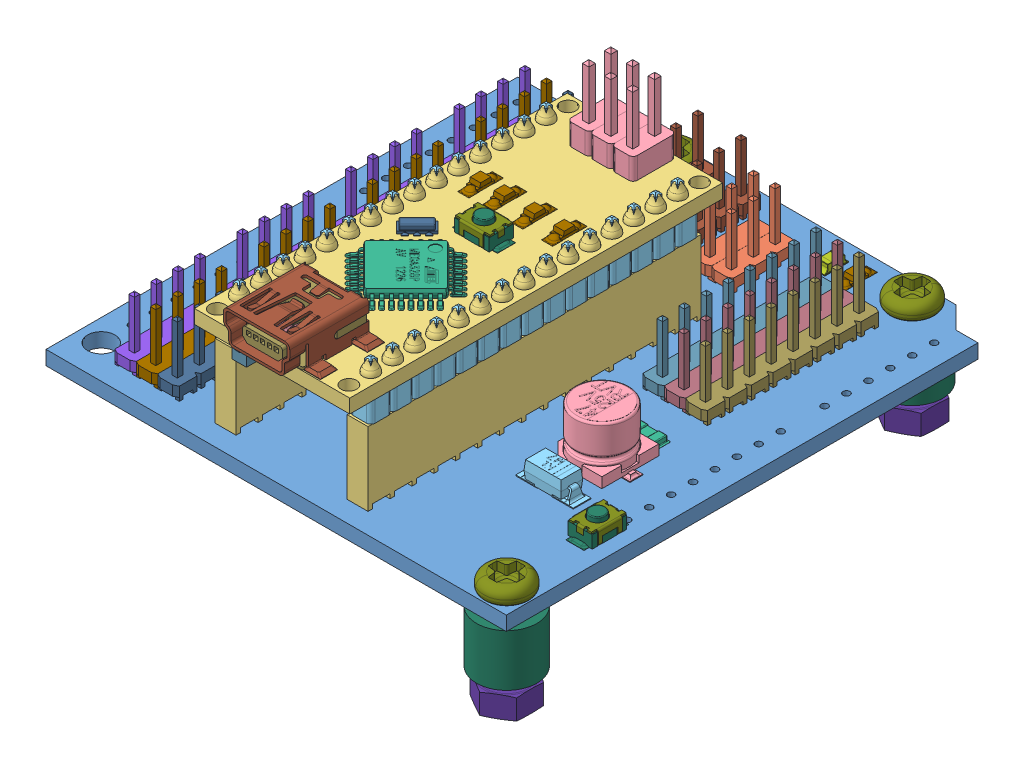
SolidWorks assembly Ensamblaje_Shield_NANO_spacer_screw_M3, configuration Predeterminado. Lengths in mm.
Overall size (54.3 32.38 59.87).
81 component instances, 35 part files, 24 mates.
Components (placement in the parent):
- Ensamblaje_Shield_NANO-2: Ensamblaje_Shield_NANO [Predeterminado] at (30.2087 16.5393 22.618) size (53.34 23.75 58.91)
  - Shield_Arduino NANO-1: Shield_Arduino NANO [Default] at (28.1337 3.1376 57.2) size (53.34 1.65 57.2)
  - Samtec-TLW-103-01-F-S-1: Samtec-TLW-103-01-F-S [Default] at (7.7639 4.0901 -3.1706) x (0 0 1) z (-1 0 0) size (7.62 10 2.49)
  - Samtec-TLW-103-01-F-S-2: Samtec-TLW-103-01-F-S [Default] at (5.2639 4.0901 -3.1706) x (0 0 1) z (-1 0 0) size (7.62 10 2.49)
  - arduino nano-1: arduino nano [Predeterminado] at (-6.7272 14.1466 6.3422) x (0 0 1) z (-1 0 0) size (45 18.6 18)
    - nano-board-1: nano-board [Predeterminado] at origin size (43.2 4.61 18)
    - 2pin_header__02-1: 2pin_header__02 [Predeterminado] at (-1.143 1.6 -7.62) size (5 11.75 2.54)
    - 2pin_header__02-2: 2pin_header__02 [Predeterminado] at (-1.143 1.6 -5.08) size (5 11.75 2.54)
    - 2pin_header__02-3: 2pin_header__02 [Predeterminado] at (-1.143 1.6 -10.16) size (5 11.75 2.54)
    - 15pin_header__-1: 15pin_header__ [Predeterminado] x (0 0 1) z (1 0 0) size (2.54 11.75 38.1)
    - 15pin_header__-2: 15pin_header__ [Predeterminado] at (0 0 -15.24) x (0 0 1) z (1 0 0) size (2.54 11.75 38.1)
    - atmega328-1: atmega328 [Predeterminado] at (23.85 1.75 -7.62) x (-0.707107 0 0.707107) z (-0.707107 0 -0.707107) size (10 1.1 10)
    - ftdi FT232rl-1: ftdi FT232rl [Predeterminado] at (29.05 0 -7.67) x (0 0 -1) z (-1 0 0) size (9.25 1.9 10.2)
    - smt_resistor222-1: smt_resistor222 [Predeterminado] at (21.86 0 -5.8) x (0 0 -1) z (-1 0 0) size (1.7 0.6 3.8)
    - smt_resistor222-2: smt_resistor222 [Predeterminado] at (21.86 0 -9) x (0 0 -1) z (-1 0 0) size (1.7 0.6 3.8)
    - smt_resistor222-3: smt_resistor222 [Predeterminado] at (36.75 0 -7.6) x (0 0 -1) z (-1 0 0) size (1.7 0.6 3.8)
    - smt_resistor222-4: smt_resistor222 [Predeterminado] at (36.75 0 -12) x (0 0 -1) z (-1 0 0) size (1.7 0.6 3.8)
    - smt_resistor222-5: smt_resistor222 [Predeterminado] at (8.2 0 -2.6) x (0 0 -1) z (-1 0 0) size (1.7 0.6 3.8)
    - led-1: led [Predeterminado] at (10.4 1.6 -2.8) size (4 0.9 1.55)
    - led-2: led [Predeterminado] at (10.4 1.6 -5.55) size (4 0.9 1.55)
    - led-3: led [Predeterminado] at (10.4 1.6 -12.5) size (4 0.9 1.55)
    - led-4: led [Predeterminado] at (10.4 1.6 -9.05) size (4 0.9 1.55)
    - 16mhz crystal - measured-1: 16mhz crystal - measured [Predeterminado] at (18.5113 1.6 -3.5541) x (0.707107 0 0.707107) z (-0.707107 0 0.707107) size (3.4 0.8 2.01)
    - MINIUSB - MEASURED-1: MINIUSB - MEASURED [Predeterminado] at (38.98 1.65 -7.62) x (0 0 1) z (-1 0 0) size (11.03 4.95 10.42)
      - MINIUSBSHELL-1: MINIUSBSHELL [Predeterminado] at origin size (11.03 3.97 9.48)
      - MINIUSBCORE-1: MINIUSBCORE [Predeterminado] at (0 0 6.7) x (-1 0 0) z (0 0 -1) size (7.7 4.5 8.2)
      - MINI USB CONTACT-1: MINI USB CONTACT [Predeterminado] at (-1.6 0 5.7) x (-1 0 0) z (0 0 -1) size (0.53 2.55 9.41)
      - MINI USB CONTACT-2: MINI USB CONTACT [Predeterminado] at (-0.8 0 5.7) x (-1 0 0) z (0 0 -1) size (0.53 2.55 9.41)
      - MINI USB CONTACT-3: MINI USB CONTACT [Predeterminado] at (0 0 5.7) x (-1 0 0) z (0 0 -1) size (0.53 2.55 9.41)
      - MINI USB CONTACT-4: MINI USB CONTACT [Predeterminado] at (0.8 0 5.7) x (-1 0 0) z (0 0 -1) size (0.53 2.55 9.41)
      - MINI USB CONTACT-5: MINI USB CONTACT [Predeterminado] at (1.6 0 5.7) x (-1 0 0) z (0 0 -1) size (0.53 2.55 9.41)
    - cap106C-1: cap106C [Predeterminado] at (37.2 0 -3.3) x (0 0 1) z (1 0 0) size (1.7 1.81 4)
    - cap106C-2: cap106C [Predeterminado] at (7.9 0 -5.6) x (0 0 -1) z (-1 0 0) size (1.7 1.81 4)
    - reset button-1: reset button [Predeterminado] at (15.25 1.6 -8.05) x (0 0 -1) z (1 0 0) size (5.21 2.15 3)
      - reset core-1: reset core [Predeterminado] at origin size (5.21 2.15 2.8)
      - reset shell-1: reset shell [Predeterminado] at (0 1.65 0) x (0 0 1) z (-1 0 0) size (3 1.65 4)
    - nano - reg-1: nano - reg [Predeterminado] at (6.1 0 -10.16) x (0 0 -1) z (-1 0 0) size (6.5 1.69 8.3)
    - NANO DIODE-1: NANO DIODE [Predeterminado] at (11.43 0 -4.2) x (0 0 1) z (1 0 0) size (4.92 1.38 1.7)
    - 189 RESISTOR PACK-1: 189 RESISTOR PACK [Predeterminado] at (15.75 0 -10.85) x (0 0 1) z (1 0 0) size (3.2 0.51 3)
    - 102 RESISTOR PACK-1: 102 RESISTOR PACK [Predeterminado] at (15.75 0 -5.2) x (0 0 1) z (1 0 0) size (3.2 0.51 3)
  - Samtec-SSW-115-01-F-S-3: Samtec-SSW-115-01-F-S [Default] at (8.5128 3.1376 24.1222) size (2.41 11.15 38.61)
  - Samtec-SSW-115-01-F-S-4: Samtec-SSW-115-01-F-S [Default] at (-6.7872 3.1376 24.1222) size (2.41 11.15 38.61)
  - 47uf CAP Dcase-1: 47uf CAP Dcase [Default] at (17.9906 3.1376 24.6048) x (0 0 -1) z (1 0 0) size (6.6 5.81 8)
  - m7 diode-1: m7 diode [Default] at (18.0456 3.1376 30.2824) size (6.66 2.35 2.5)
  - smt_resistor222_a-1: smt_resistor222_a [Default] at (18.3832 3.1376 19.7626) x (0 0 -1) z (1 0 0) size (1.7 0.6 3.8)
  - nano - reg-1: nano - reg [Predeterminado] at (1.246 3.1376 24.0398) x (0 0 1) z (-1 0 0) size (6.5 1.69 8.3)
  - cap106C-1: cap106C [Predeterminado] at (1.2297 3.1376 32.7528) x (0 0 1) z (-1 0 0) size (1.7 1.81 4)
  - smt_resistor222_a-2: smt_resistor222_a [Default] at (1.378 3.1376 29.6673) x (0 0 -1) z (1 0 0) size (1.7 0.6 3.8)
  - smt_resistor222_a-3: smt_resistor222_a [Default] at (1.364 3.1376 18.2634) x (0 0 -1) z (1 0 0) size (1.7 0.6 3.8)
  - cap106C-2: cap106C [Predeterminado] at (1.6627 3.1376 15.2796) x (0 0 1) z (-1 0 0) size (1.7 1.81 4)
  - led-1: led [Predeterminado] at (14.5957 3.1376 -8.0824) x (0 0 -1) z (1 0 0) size (4 0.9 1.55)
  - reset button-1: reset button [Predeterminado] at (25.102 3.1376 32.2333) x (0 0 -1) z (1 0 0) size (5.21 2.15 3)
    - reset core-1: reset core [Predeterminado] at origin size (5.21 2.15 2.8)
    - reset shell-1: reset shell [Predeterminado] at (0 1.65 0) x (0 0 1) z (-1 0 0) size (3 1.65 4)
  - blm21-1: blm21 [Default] at (11.9193 3.1376 -8.0299) x (0 0 -1) z (1 0 0) size (2.76 0.95 1.32)
  - Samtec-TLW-104-01-F-S_N-1: Samtec-TLW-104-01-F-S_N [Default] at (-18.4832 4.0901 38.492) x (0 0 -1) z (1 0 0) size (10.16 10 2.49)
  - Samtec-TLW-104-01-F-S_N-2: Samtec-TLW-104-01-F-S_N [Default] at (-18.4832 4.0901 25.942) x (0 0 -1) z (1 0 0) size (10.16 10 2.49)
  - Samtec-TLW-104-01-F-S_N-3: Samtec-TLW-104-01-F-S_N [Default] at (-18.4832 4.0901 13.392) x (0 0 -1) z (1 0 0) size (10.16 10 2.49)
  - Samtec-TLW-104-01-F-S_N-4: Samtec-TLW-104-01-F-S_N [Default] at (-18.4832 4.0901 0.842) x (0 0 -1) z (1 0 0) size (10.16 10 2.49)
  - Samtec-TLW-104-01-F-S_R-1: Samtec-TLW-104-01-F-S_R [Default] at (-15.994 4.0901 38.492) x (0 0 1) z (-1 0 0) size (10.16 10 2.49)
  - Samtec-TLW-104-01-F-S_R-2: Samtec-TLW-104-01-F-S_R [Default] at (-15.994 4.0901 25.942) x (0 0 1) z (-1 0 0) size (10.16 10 2.49)
  - Samtec-TLW-104-01-F-S_R-3: Samtec-TLW-104-01-F-S_R [Default] at (-15.994 4.0901 13.392) x (0 0 1) z (-1 0 0) size (10.16 10 2.49)
  - Samtec-TLW-104-01-F-S_R-4: Samtec-TLW-104-01-F-S_R [Default] at (-15.994 4.0901 0.842) x (0 0 1) z (-1 0 0) size (10.16 10 2.49)
  - Samtec-TLW-104-01-F-S_B-1: Samtec-TLW-104-01-F-S_B [Default] at (-13.5048 4.0901 38.492) x (0 0 -1) z (1 0 0) size (10.16 10 2.49)
  - Samtec-TLW-104-01-F-S_B-2: Samtec-TLW-104-01-F-S_B [Default] at (-13.5048 4.0901 25.942) x (0 0 -1) z (1 0 0) size (10.16 10 2.49)
  - Samtec-TLW-104-01-F-S_B-3: Samtec-TLW-104-01-F-S_B [Default] at (-13.5048 4.0901 13.392) x (0 0 -1) z (1 0 0) size (10.16 10 2.49)
  - Samtec-TLW-104-01-F-S_B-4: Samtec-TLW-104-01-F-S_B [Default] at (-13.5048 4.0901 0.842) x (0 0 -1) z (1 0 0) size (10.16 10 2.49)
  - Samtec-TLW-104-01-F-S_W-1: Samtec-TLW-104-01-F-S_W [Default] at (-4.0059 4.0901 -4.7024) x (0 0 -1) z (1 0 0) size (10.16 10 2.49)
  - Samtec-TLW-104-01-F-S_W-2: Samtec-TLW-104-01-F-S_W [Default] at (0.9469 4.0901 -4.7452) x (0 0 -1) z (1 0 0) size (10.16 10 2.49)
  - Samtec-TLW-108-01-F-S_B-1: Samtec-TLW-108-01-F-S_B [Default] at (19.5362 4.0901 5.2512) x (0 0 -1) z (1 0 0) size (20.32 10 2.49)
  - Samtec-TLW-108-01-F-S_R-1: Samtec-TLW-108-01-F-S_R [Default] at (17.047 4.0901 5.2512) x (0 0 1) z (-1 0 0) size (20.32 10 2.49)
  - Samtec-TLW-108-01-F-S_N-1: Samtec-TLW-108-01-F-S_N [Default] at (14.5578 4.0901 5.2512) x (0 0 1) z (-1 0 0) size (20.32 10 2.49)
- separador-1: separador [Predeterminado] at (55.8024 18.0269 65.848) x (1 0 0) z (0 -1 0) size (7 7 6)
- M3x10 Philips Screw-1: M3x10 Philips Screw [Predeterminado] at (55.8024 19.6769 65.848) x (1 0 0) z (0 1 0) size (5.3 5.3 11.8)
- M3 Nut-1: M3 Nut [Predeterminado] at (55.8024 12.5269 65.848) x (1 0 0) z (0 1 0) size (6.27 6.27 2.71)
- M3 Nut-2: M3 Nut [Predeterminado] at (50.7224 7.0269 13.778) x (0.999652 0 0.026398) z (0 -1 0) size (6.27 6.27 2.71)
- separador-2: separador [Predeterminado] at (50.7224 18.0269 13.778) x (1 0 0) z (0 -1 0) size (7 7 6)
- M3x10 Philips Screw-2: M3x10 Philips Screw [Predeterminado] at (50.7224 19.6769 13.778) x (1 0 0) z (0 1 0) size (5.3 5.3 11.8)
- M3x10 Philips Screw-3: M3x10 Philips Screw [Predeterminado] at (22.7824 19.6769 13.778) x (1 0 0) z (0 1 0) size (5.3 5.3 11.8)
- separador-3: separador [Predeterminado] at (22.7824 18.0269 13.778) x (1 0 0) z (0 -1 0) size (7 7 6)
- M3 Nut-3: M3 Nut [Predeterminado] at (22.7824 7.0269 13.778) x (1 0 0) z (0 -1 0) size (6.27 6.27 2.71)
Mates (geometry in assembly coordinates):
- Coincidente2: coincident: plane of Ensamblaje_Shield_NANO-2/Shield_Arduino NANO-1 through (58.3424 18.0269 79.818) normal (0 -1 0); plane of ? through (22.7824 18.0269 13.778) normal (0 1 0)
- Coincidente3: coincident: plane of Ensamblaje_Shield_NANO-2/Shield_Arduino NANO-1 through (58.3424 18.0269 79.818) normal (0 -1 0); plane of ? through (55.8024 18.0269 65.848) normal (0 1 0)
- Coincidente4: coincident: plane of Ensamblaje_Shield_NANO-2/Shield_Arduino NANO-1 through (58.3424 18.0269 79.818) normal (0 -1 0); plane of ? through (50.7224 18.0269 13.778) normal (0 1 0)
- Concéntrica2: concentric: circle of Ensamblaje_Shield_NANO-2/Shield_Arduino NANO-1; circle of ?
- Concéntrica3: concentric: circle of Ensamblaje_Shield_NANO-2/Shield_Arduino NANO-1; circle of ?
- Concéntrica4: concentric: circle of Ensamblaje_Shield_NANO-2/Shield_Arduino NANO-1; circle of ?
- Coincidente5: coincident: plane of Ensamblaje_Shield_NANO-2/Shield_Arduino NANO-1 through (58.3424 19.6769 79.818) normal (0 1 0); plane of M3x10 Philips Screw-1 through (55.8024 19.6769 64.248) normal (0 -1 0)
- Concéntrica5: concentric: circle of Ensamblaje_Shield_NANO-2/Shield_Arduino NANO-1; circle of M3x10 Philips Screw-1
- Coincidente6: coincident: plane of Ensamblaje_Shield_NANO-2/Shield_Arduino NANO-1 through (58.3424 18.0269 79.818) normal (0 -1 0); plane of separador-1 through (55.8024 18.0269 65.848) normal (0 1 0)
- Concéntrica6: concentric: circle of Ensamblaje_Shield_NANO-2/Shield_Arduino NANO-1; circle of separador-1
- Distancia1: distance = 1 mm: plane of M3 Nut-1 through (55.8024 11.0269 65.848) normal (0 1 0); plane of separador-1 through (55.8024 12.0269 65.848) normal (0 -1 0)
- Concéntrica7: concentric: circle of separador-1; circle of M3 Nut-1
- Coincidente8: coincident: plane of Ensamblaje_Shield_NANO-2/Shield_Arduino NANO-1 through (58.3424 19.6769 79.818) normal (0 1 0); plane of M3x10 Philips Screw-2 through (50.7224 19.6769 12.178) normal (0 -1 0)
- Coincidente9: coincident: plane of Ensamblaje_Shield_NANO-2/Shield_Arduino NANO-1 through (58.3424 18.0269 79.818) normal (0 -1 0); plane of separador-2 through (50.7224 18.0269 13.778) normal (0 1 0)
- Coincidente10: coincident: plane of Ensamblaje_Shield_NANO-2/Shield_Arduino NANO-1 through (58.3424 19.6769 79.818) normal (0 1 0); plane of M3x10 Philips Screw-3 through (22.7824 19.6769 12.178) normal (0 -1 0)
- Coincidente11: coincident: plane of Ensamblaje_Shield_NANO-2/Shield_Arduino NANO-1 through (58.3424 18.0269 79.818) normal (0 -1 0); plane of separador-3 through (22.7824 18.0269 13.778) normal (0 1 0)
- Concéntrica8: concentric: circle of Ensamblaje_Shield_NANO-2/Shield_Arduino NANO-1; circle of separador-2
- Concéntrica9: concentric: circle of Ensamblaje_Shield_NANO-2/Shield_Arduino NANO-1; circle of M3x10 Philips Screw-2
- Concéntrica10: concentric: circle of Ensamblaje_Shield_NANO-2/Shield_Arduino NANO-1; circle of M3x10 Philips Screw-3
- Concéntrica11: concentric: circle of Ensamblaje_Shield_NANO-2/Shield_Arduino NANO-1; circle of separador-3
- Concéntrica12: concentric: circle of M3 Nut-2; circle of separador-2
- Concéntrica13: concentric: circle of separador-3; circle of M3 Nut-3
- Distancia2: distance = 1 mm: plane of M3 Nut-3 through (22.7824 11.0269 13.778) normal (0 1 0); plane of separador-3 through (22.7824 12.0269 13.778) normal (0 -1 0)
- Distancia3: distance = 1 mm: plane of M3 Nut-2 through (50.7224 11.0269 13.778) normal (0 1 0); plane of separador-2 through (50.7224 12.0269 13.778) normal (0 -1 0)
